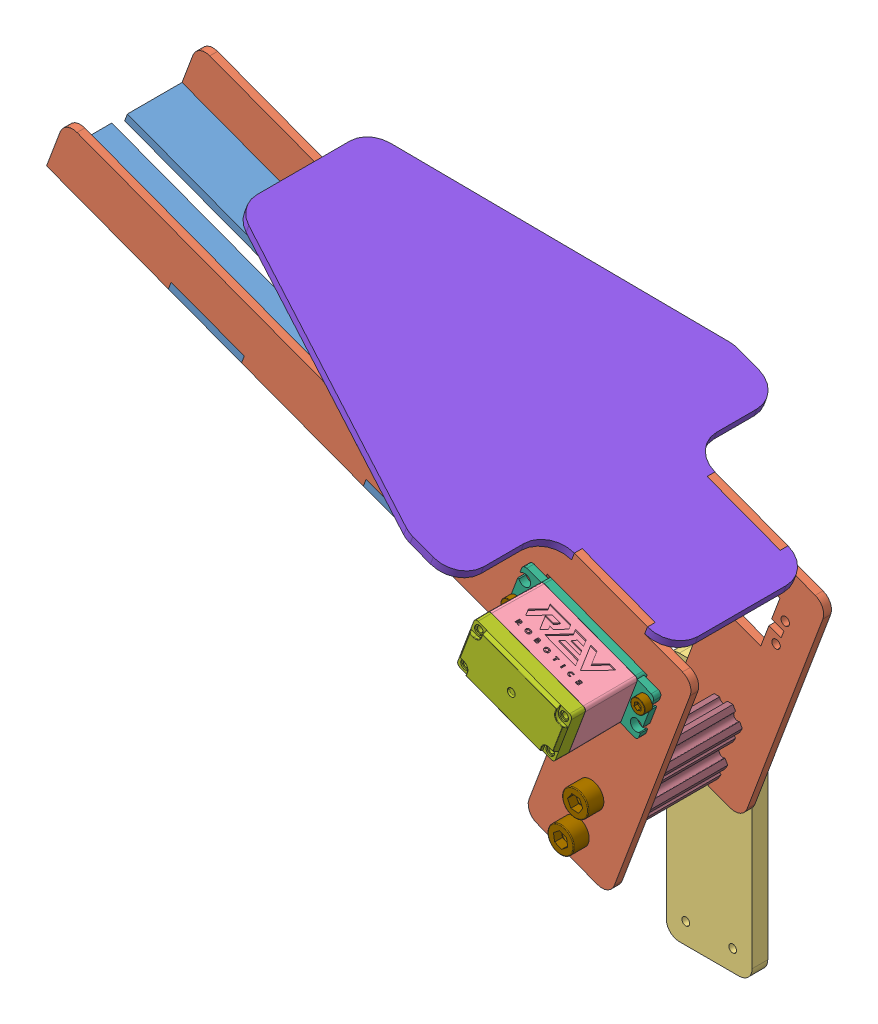
SolidWorks assembly M04.04 Lançador, configuration Valor predeterminado. Lengths in mm.
Overall size (267.79 233.17 125).
26 component instances, 13 part files, 39 mates.
Components (placement in the parent):
- Lançador-1: Lançador [Valor predeterminado] at (7.1601 14.3572 4) x (0.936354 -0.351057 0) z (0 0 1) size (250 96 54)
  - M04.04.01.base_aviaozinho (1)-1: M04.04.01.base_aviaozinho (1) [Valor predeterminado] at (-181.8086 4.9003 211.5885) x (1 0 0) z (0 -1 0) size (180 54 3)
  - M04.04.02.lateral_aviaozino (1)-1: M04.04.02.lateral_aviaozino (1) [Valor predeterminado] at (-181.8086 21.9003 160.5885) size (250 96 3)
  - M04.04.02.lateral_aviaozino (1)-2: M04.04.02.lateral_aviaozino (1) [Valor predeterminado] at (-181.8086 21.9003 211.5885) size (250 96 3)
- M04.04.03.suporte aviãozinho-1: M04.04.03.suporte aviãozinho [Valor predeterminado] at (21.6914 -64.5997 158.5885) size (33 96 6)
- Servo REV-2: Servo REV [Valor predeterminado] at (12.5071 33.6724 252.7045) x (-0.351057 -0.936354 0) z (0.936354 -0.351057 0) size (20.15 43.7 54)
  - M04.01.04.04.E-1: M04.01.04.04.E [Valor predeterminado] at (-1.9374 4.766 34.4654) size (20.15 20.1 40.15)
  - M04.01.04.05.D-1: M04.01.04.05.D [Valor predeterminado] at (-1.9374 34.866 24.4128) x (-1 0 0) z (0 0 -1) size (17.24 14.7 17.23)
  - M04.01.04.06.C-1: M04.01.04.06.C [Valor predeterminado] at (-1.9374 4.766 34.4654) size (19.8 13.29 54)
  - M04.01.04.07.A-1: M04.01.04.07.A [Valor predeterminado] at (-1.9374 4.766 34.4654) size (20.15 8.55 40.13)
- M04.04.08.Protecao aviao-1: M04.04.08.Protecao aviao [Valor predeterminado] at (76.7666 35.6787 191.5885) x (0 0 -1) z (0.351057 0.936354 0) size (125 180 3)
- socket head cap screw_iso-12: socket head cap screw_iso [ISO 4762 M3 x 8 - 8N] at (20.529 27.394 224.2885) x (0 0 -1) z (0.999931 -0.011783 0) size (11 5.5 5.5)
- socket head cap screw_iso-13: socket head cap screw_iso [ISO 4762 M3 x 8 - 8N] at (70.3891 19.3802 224.2885) x (0 0 -1) z (-0.588578 -0.80844 0) size (11 5.5 5.5)
- socket head cap screw_iso-15: socket head cap screw_iso [ISO 4762 M6 x 12 - 12N] at (46.6914 -24.5997 152.5885) x (0 0 1) z (-0.355082 0.934835 0) size (18 10 10)
- socket head cap screw_iso-17: socket head cap screw_iso [ISO 4762 M6 x 12 - 12N] at (41.0744 -39.5813 152.5885) x (0 0 1) z (0.001298 -0.999999 0) size (18 10 10)
- torque nut 08_iso-5: torque nut 08_iso [ISO 10511-M3-N] at (70.3891 19.3802 214.0385) x (0.923728 0.383049 0) z (0 0 -1) size (5.5 6.35 3.9)
- torque nut 08_iso-6: torque nut 08_iso [ISO 10511-M3-N] at (20.529 27.394 214.0385) x (0.923728 0.383049 0) z (0 0 -1) size (5.5 6.35 3.9)
- M04.04.09.Adaptador servo REV aviao-1: M04.04.09.Adaptador servo REV aviao [Default] at (36.0462 26.9162 204.2385) x (-0.817476 0.575963 0) z (0 0 -1) size (40 13 7)
- M04.04.10.Trava aviao-1: M04.04.10.Trava aviao [Valor predeterminado] at (36.0462 26.9162 200.7385) x (-0.575963 -0.817476 0) z (0 0 -1) size (24 33 6)
- socket head cap screw_iso-18: socket head cap screw_iso [ISO 4762 M3 x 10 - 10N] at (29.5064 31.5239 191.7385) x (0 0 1) z (-1 0 0) size (13 5.5 5.5)
- socket head cap screw_iso-19: socket head cap screw_iso [ISO 4762 M3 x 10 - 10N] at (42.586 22.3085 191.7385) x (0 0 1) z (-1 0 0) size (13 5.5 5.5)
- socket head cap screw_iso-20: socket head cap screw_iso [ISO 4762 M3 x 6 - 6N] at (36.0462 26.9162 199.9885) x (0 0 1) z (-1 0 0) size (9 5.5 5.5)
- socket head cap screw_iso-25: socket head cap screw_iso [ISO 4762 M6 x 12 - 12N] at (46.6914 -24.5997 224.5885) x (0 0 -1) z (-0.076187 -0.997094 0) size (18 10 10)
- socket head cap screw_iso-26: socket head cap screw_iso [ISO 4762 M6 x 12 - 12N] at (41.0744 -39.5813 224.5885) x (0 0 -1) z (-0.365248 -0.93091 0) size (18 10 10)
- Churros laterais aviao-1: Churros laterais aviao [Valor predeterminado] at (41.0744 -39.5813 252.5885) x (1 0 0) z (0 1 0) size (14.43 48 12.5)
- Churros laterais aviao-2: Churros laterais aviao [Valor predeterminado] at (46.6914 -24.5997 252.5885) x (1 0 0) z (0 1 0) size (14.43 48 12.5)
Mates (geometry in assembly coordinates):
- Concêntrico3: concentric aligned: cylinder of Lançador-1/M04.04.02.lateral_aviaozino (1)-2 through (20.529 27.394 218.5885) axis (0 0 -1) radius 1.625; cylinder of Servo REV-2/M04.01.04.06.C-1 through (20.529 27.394 218.5885) axis (0 0 -1) radius 2.25
- Concêntrico6: concentric aligned: cylinder of Lançador-1/M04.04.02.lateral_aviaozino (1)-2 through (24.0395 36.7576 218.5885) axis (0 0 -1) radius 1.625; cylinder of Servo REV-2/M04.01.04.06.C-1 through (24.0395 36.7576 218.5885) axis (0 0 -1) radius 2.25
- Coincidente9: coincident anti-aligned: plane of Lançador-1/M04.04.02.lateral_aviaozino (1)-2 through (-155.3889 98.6888 218.5885) normal (0 0 1); plane of Servo REV-2/M04.01.04.06.C-1 through (45.459 23.3871 218.5885) normal (0 0 -1)
- Concêntrico10: concentric aligned: cylinder of Lançador-1/M04.04.02.lateral_aviaozino (1)-2 through (46.6914 -24.5997 218.5885) axis (0 0 -1) radius 3; cylinder of M04.04.03.suporte aviãozinho-1 through (46.6914 -24.5997 164.5885) axis (0 0 -1) radius 3
- Coincidente19: coincident anti-aligned: plane of Lançador-1/M04.04.02.lateral_aviaozino (1)-1 through (59.5043 18.1213 167.5885) normal (0.936354 -0.351057 0); plane of M04.04.08.Protecao aviao-1 through (68.4563 41.9983 191.5885) normal (-0.936354 0.351057 0)
- Coincidente20: coincident anti-aligned: plane of Lançador-1/M04.04.02.lateral_aviaozino (1)-1 through (-155.3889 98.6888 167.5885) normal (0 0 1); plane of M04.04.08.Protecao aviao-1 through (77.8198 38.4877 167.5885) normal (0 0 -1)
- Coincidente21: coincident aligned: plane of Lançador-1/M04.04.02.lateral_aviaozino (1)-1 through (-146.437 122.5659 167.5885) normal (0.351057 0.936354 0); plane of M04.04.08.Protecao aviao-1 through (77.8198 38.4877 191.5885) normal (0.351057 0.936354 0)
- Concêntrico19: concentric aligned: cylinder of M04.04.03.suporte aviãozinho-1 through (46.6914 -24.5997 164.5885) axis (0 0 -1) radius 3; cylinder of socket head cap screw_isop-15 through (46.6914 -24.5997 120.8385) axis (0 0 -1) radius 5
- Coincidente25: coincident anti-aligned: plane of M04.04.03.suporte aviãozinho-1 through (26.6914 -105.5997 158.5885) normal (0 0 -1); plane of socket head cap screw_isop-15 through (51.3655 -22.8243 158.5885) normal (0 0 1)
- Concêntrico21: concentric aligned: cylinder of Lançador-1/M04.04.02.lateral_aviaozino (1)-1 through (41.0744 -39.5813 167.5885) axis (0 0 -1) radius 3; cylinder of socket head cap screw_isop-17 through (41.0744 -39.5813 120.8385) axis (0 0 -1) radius 3
- Coincidente26: coincident anti-aligned: plane of M04.04.03.suporte aviãozinho-1 through (26.6914 -105.5997 158.5885) normal (0 0 -1); plane of socket head cap screw_isop-17 through (36.0744 -39.5878 158.5885) normal (0 0 1)
- Concêntrico22: concentric anti-aligned: cylinder of Servo REV-2/M04.01.04.06.C-1 through (70.3891 19.3802 218.5885) axis (0 0 -1) radius 2.25; cylinder of socket head cap screw_iso-13 through (70.3891 19.3802 256.0385) axis (0 0 1) radius 1.5
- Concêntrico23: concentric anti-aligned: cylinder of Servo REV-2/M04.01.04.06.C-1 through (20.529 27.394 218.5885) axis (0 0 -1) radius 2.25; cylinder of socket head cap screw_iso-12 through (20.529 27.394 256.0385) axis (0 0 1) radius 1.5
- Coincidente28: coincident: line of Servo REV-2/M04.01.04.04.E-1 through (23.7889 22.2736 221.2885) axis (0.351057 0.936354 0); plane of socket head cap screw_iso-12 through (20.5614 30.1438 221.2885) normal (0 0 -1)
- Coincidente29: coincident: line of Servo REV-2/M04.01.04.04.E-1 through (67.1291 24.5006 221.2885) axis (-0.351057 -0.936354 0); plane of socket head cap screw_iso-13 through (72.6123 17.7616 221.2885) normal (0 0 -1)
- Concêntrico176: concentric aligned: cylinder of Lançador-1/M04.04.02.lateral_aviaozino (1)-2 through (70.3891 19.3802 218.5885) axis (0 0 -1) radius 1.625; cylinder of torque nut 08_iso-5 through (70.3891 19.3802 194.9885) axis (0 0 -1) radius 1.5
- Coincidente236: coincident anti-aligned: plane of Lançador-1/M04.04.02.lateral_aviaozino (1)-2 through (-155.3889 98.6888 215.5885) normal (0 0 -1); plane of torque nut 08_iso-5 through (71.6054 16.447 215.5885) normal (0 0 1)
- Concêntrico177: concentric aligned: cylinder of Lançador-1/M04.04.02.lateral_aviaozino (1)-2 through (20.529 27.394 218.5885) axis (0 0 -1) radius 1.625; cylinder of torque nut 08_iso-6 through (20.529 27.394 194.9885) axis (0 0 -1) radius 1.5
- Coincidente237: coincident anti-aligned: plane of Lançador-1/M04.04.02.lateral_aviaozino (1)-2 through (-155.3889 98.6888 215.5885) normal (0 0 -1); plane of torque nut 08_iso-6 through (21.7453 24.4608 215.5885) normal (0 0 1)
- Coincidente238: coincident anti-aligned: plane of Servo REV-2/M04.01.04.05.D-1 through (36.0462 26.9162 204.2385) normal (0 0 -1); plane of M04.04.09.Adaptador servo REV aviao-1 through (36.0462 26.9162 204.2385) normal (0 0 1)
- Concêntrico178: concentric aligned: circle of Servo REV-2/D-1; cylinder of M04.04.09.Adaptador servo REV aviao-1 through (36.0462 26.9162 204.2385) axis (0 0 1) radius 2.8
- Concêntrico179: concentric anti-aligned: cylinder of M04.04.09.Adaptador servo REV aviao-1 through (36.0462 26.9162 202.9885) axis (0 0 -1) radius 4.25; cylinder of M04.04.10.Trava aviao-1 through (36.0462 26.9162 194.7385) axis (0 0 1) radius 3
- Coincidente239: coincident anti-aligned: plane of M04.04.09.Adaptador servo REV aviao-1 through (36.0462 26.9162 200.7385) normal (0 0 -1); plane of M04.04.10.Trava aviao-1 through (36.0462 26.9162 200.7385) normal (0 0 1)
- Concêntrico180: concentric anti-aligned: circle of Adaptador servo REV aviao-1; cylinder of M04.04.10.Trava aviao-1 through (29.5064 31.5239 194.7385) axis (0 0 1) radius 1.6
- Concêntrico181: concentric anti-aligned: cylinder of M04.04.10.Trava aviao-1 through (29.5064 31.5239 194.7385) axis (0 0 1) radius 1.6; cylinder of socket head cap screw_iso-18 through (29.5064 31.5239 159.9885) axis (0 0 -1) radius 2.75
- Coincidente240: coincident anti-aligned: plane of M04.04.10.Trava aviao-1 through (36.0462 26.9162 194.7385) normal (0 0 -1); plane of socket head cap screw_iso-18 through (29.5064 34.2739 194.7385) normal (0 0 1)
- Concêntrico182: concentric anti-aligned: cylinder of M04.04.10.Trava aviao-1 through (42.586 22.3085 194.7385) axis (0 0 1) radius 1.6; cylinder of socket head cap screw_iso-19 through (42.586 22.3085 159.9885) axis (0 0 -1) radius 2.75
- Coincidente241: coincident anti-aligned: plane of M04.04.10.Trava aviao-1 through (36.0462 26.9162 194.7385) normal (0 0 -1); plane of socket head cap screw_iso-19 through (42.586 25.0585 194.7385) normal (0 0 1)
- Concêntrico183: concentric aligned: cylinder of M04.04.09.Adaptador servo REV aviao-1 through (36.0462 26.9162 204.2385) axis (0 0 -1) radius 1.6; cylinder of socket head cap screw_iso-20 through (36.0462 26.9162 168.2385) axis (0 0 -1) radius 2.75
- Coincidente242: coincident anti-aligned: plane of M04.04.09.Adaptador servo REV aviao-1 through (36.0462 26.9162 202.9885) normal (0 0 -1); plane of socket head cap screw_iso-20 through (36.0462 29.6662 202.9885) normal (0 0 1)
- Coincidente243: coincident anti-aligned: plane of Lançador-1/M04.04.02.lateral_aviaozino (1)-1 through (-155.3889 98.6888 164.5885) normal (0 0 -1); plane of M04.04.03.suporte aviãozinho-1 through (26.6914 -105.5997 164.5885) normal (0 0 1)
- Concêntrico192: concentric anti-aligned: cylinder of Lançador-1/M04.04.02.lateral_aviaozino (1)-2 through (46.6914 -24.5997 218.5885) axis (0 0 -1) radius 3; cylinder of socket head cap screw_iso-25 through (46.6914 -24.5997 256.3385) axis (0 0 1) radius 3
- Concêntrico193: concentric anti-aligned: cylinder of Lançador-1/M04.04.02.lateral_aviaozino (1)-2 through (41.0744 -39.5813 218.5885) axis (0 0 -1) radius 3; cylinder of socket head cap screw_iso-26 through (41.0744 -39.5813 256.3385) axis (0 0 1) radius 3
- Coincidente252: coincident anti-aligned: plane of Lançador-1/M04.04.02.lateral_aviaozino (1)-2 through (-155.3889 98.6888 218.5885) normal (0 0 1); plane of socket head cap screw_iso-26 through (45.729 -41.4076 218.5885) normal (0 0 -1)
- Coincidente253: coincident anti-aligned: plane of Lançador-1/M04.04.02.lateral_aviaozino (1)-2 through (-155.3889 98.6888 218.5885) normal (0 0 1); plane of socket head cap screw_iso-25 through (51.6768 -24.9806 218.5885) normal (0 0 -1)
- Concêntrico194: concentric anti-aligned: cylinder of socket head cap screw_iso-26 through (41.0744 -39.5813 256.3385) axis (0 0 1) radius 3; cylinder of Churros laterais aviao-1 through (41.0744 -39.5813 215.5885) axis (0 0 -1) radius 2.79
- Coincidente254: coincident anti-aligned: plane of Lançador-1/M04.04.02.lateral_aviaozino (1)-2 through (-155.3889 98.6888 215.5885) normal (0 0 -1); plane of Churros laterais aviao-1 through (46.4871 -36.4563 215.5885) normal (0 0 1)
- Concêntrico195: concentric anti-aligned: cylinder of socket head cap screw_iso-25 through (46.6914 -24.5997 256.3385) axis (0 0 1) radius 3; cylinder of Churros laterais aviao-2 through (46.6914 -24.5997 215.5885) axis (0 0 -1) radius 2.79
- Coincidente255: coincident anti-aligned: plane of Lançador-1/M04.04.02.lateral_aviaozino (1)-2 through (-155.3889 98.6888 215.5885) normal (0 0 -1); plane of Churros laterais aviao-2 through (52.104 -21.4747 215.5885) normal (0 0 1)
